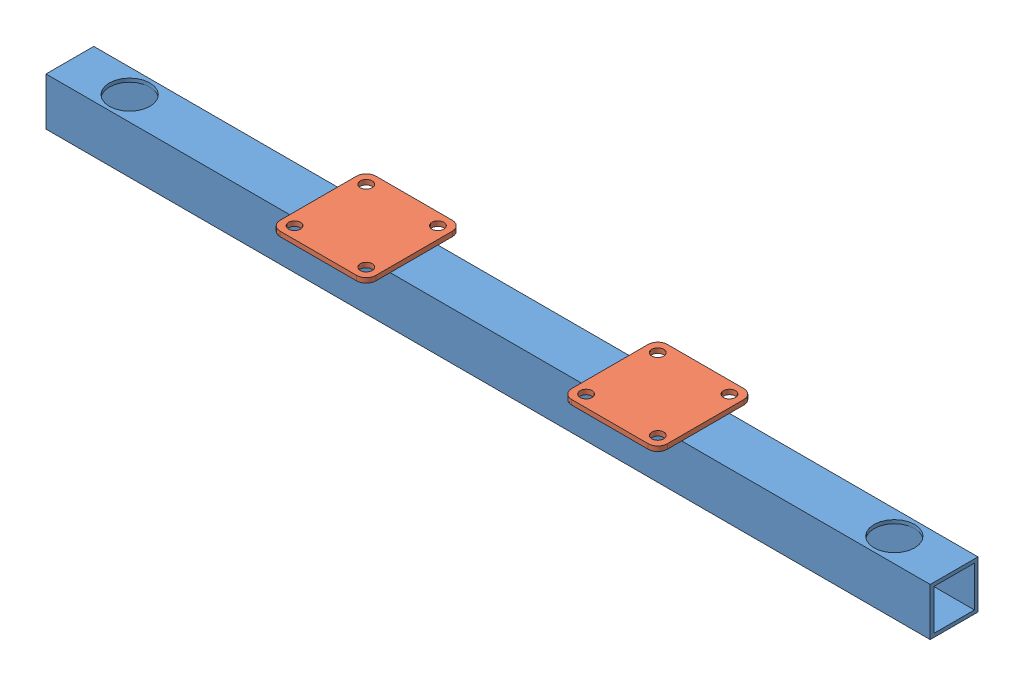
SolidWorks assembly Assemblage1, configuration Défaut. Lengths in mm.
Overall size (370 22 40).
3 component instances, 2 part files, 8 mates.
Components (placement in the parent):
- Traverse-1: Traverse [Défaut] at (-26.2077 8.0605 -17.5725) size (370 20 20)
- Platine-1: Platine [Défaut] at (34.3467 10.0605 -8.9639) x (0 0 1) z (1 0 0) size (40 2 40)
- Platine-2: Platine [Défaut] at (-86.7621 8.0605 -8.9639) x (0 0 1) z (-1 0 0) size (40 2 40)
Mates (geometry in assembly coordinates):
- Coïncidente9: coincident anti-aligned: plane of Traverse-1 through (158.7923 8.0605 -17.5725) normal (0 1 0); plane of Platine-2 through (-86.7621 8.0605 -8.9639) normal (0 -1 0)
- Coïncidente11: coincident anti-aligned: plane of Traverse-1 through (158.7923 8.0605 -17.5725) normal (0 1 0); plane of Platine-1 through (34.3467 8.0605 -8.9639) normal (0 -1 0)
- Parallèle2: parallel anti-aligned: line of Traverse-1 through (158.7923 8.0605 2.4275) axis (-1 0 0); line of Platine-1 through (18.7923 10.0605 12.4275) axis (1 0 0)
- Parallèle3: parallel aligned: line of Traverse-1 through (158.7923 8.0605 2.4275) axis (-1 0 0); line of Platine-2 through (-71.2077 10.0605 12.4275) axis (-1 0 0)
- Coïncidente18: coincident anti-aligned: line of Platine-1 through (18.7923 10.0605 12.4275) axis (1 0 0); line of Platine-2 through (-71.2077 10.0605 12.4275) axis (-1 0 0)
- Coïncidente21: coincident: point of Platine-1
- Distance2: distance = 41 mm: line of Platine-1 through (14.7923 8.0605 -23.5725) axis (0 0 1)
- Distance3: distance = 41 mm: line of Platine-2 through (-67.2077 8.0605 -23.5725) axis (0 0 1)
